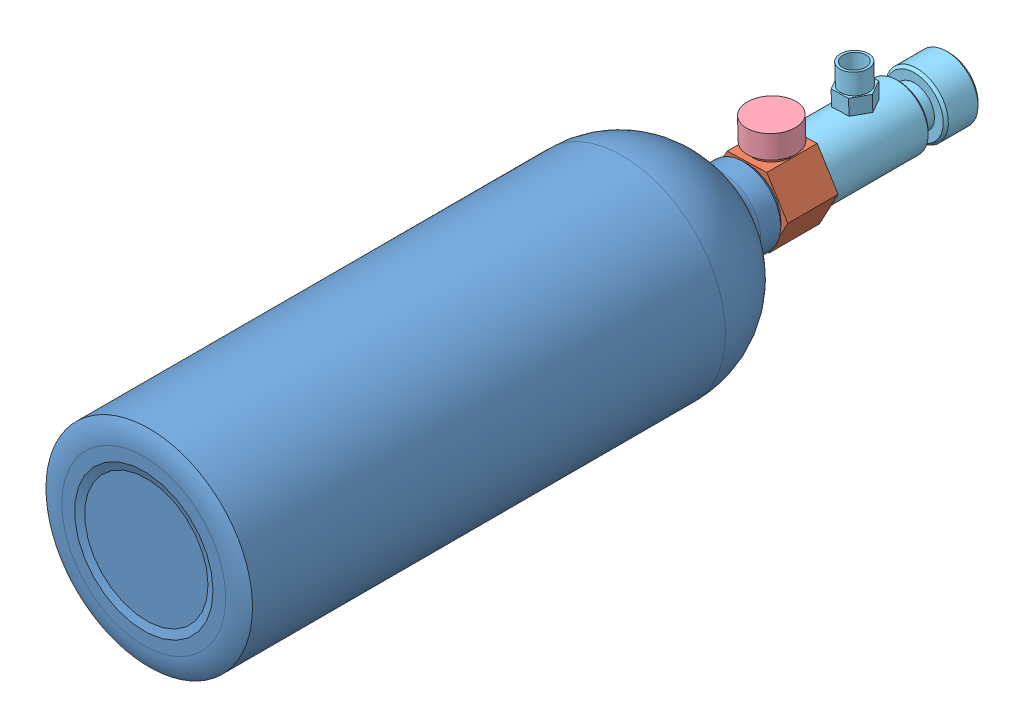
SolidWorks assembly Assem1, configuration Default. Lengths in mm.
Overall size (82 82 328.98).
5 component instances, 5 part files, 10 mates.
Components (placement in the parent):
- SE_01_2_1001-1: SE_01_2_1001 [Default] at origin size (82 82 240)
- SE_01_2_1002-1: SE_01_2_1002 [Default] at (0 0 -186.7314) x (-0.99947 -0.032561 0) z (0 0 -1) size (31.5 40.28 51)
- SE_01_2_1003-1: SE_01_2_1003 [Default] at (0 0 -220.7314) x (0.990256 -0.139258 0) z (0.139258 0.990256 0) size (18.5 2 18.5)
- SE_01_2_1004-1: SE_01_2_1004 [Default] at (-0.8023 24.6268 -196.7314) x (-0.179641 -0.005852 0.983715) z (0.032561 -0.99947 0) size (19 19 9)
- SE_01_2_1005-1: SE_01_2_1005 [Default] at (0 0 -251.5061) x (0.99947 0.032561 0) z (-0.032561 0.99947 0) size (70.53 79.28 39)
Mates (geometry in assembly coordinates):
- Concentric1: concentric anti-aligned: cylinder of SE_01_2_1001-1 through (0 0 52.2686) axis (0 0 1) radius 8; cylinder of SE_01_2_1002-1 through (0 0 -171.7314) axis (0 0 -1) radius 8
- Coincident1: coincident anti-aligned: plane of SE_01_2_1001-1 through (-8 0 -186.7314) normal (0 0 -1); plane of SE_01_2_1002-1 through (0 0 -186.7314) normal (0 0 1)
- Concentric2: concentric aligned: cylinder of SE_01_2_1002-1 through (-0.7372 22.6279 -196.7314) axis (0.032561 -0.99947 0) radius 7.5; cylinder of SE_01_2_1004-1 through (-0.7372 22.6279 -196.7314) axis (0.032561 -0.99947 0) radius 7.5
- Coincident2: coincident anti-aligned: plane of SE_01_2_1002-1 through (-0.7372 22.6279 -196.7314) normal (-0.032561 0.99947 0); plane of SE_01_2_1004-1 through (-0.7372 22.6279 -196.7314) normal (0.032561 -0.99947 0)
- Tangent8: tangent: plane of SE_01_2_1002-1 through (8.7454 0.2849 -221.7314) normal (0 0 1); torus of SE_01_2_1003-1
- Tangent9: tangent: cylinder of SE_01_2_1002-1 through (0 0 -227.3886) axis (0 0 -1) radius 7.25; torus of SE_01_2_1003-1
- Tangent10: tangent: plane of SE_01_2_1002-1 through (7.2462 0.2361 -219.7314) normal (0 0 -1); torus of SE_01_2_1003-1
- Concentric3: concentric aligned: cylinder of SE_01_2_1002-1 through (0 0 -216.7314) axis (0 0 1) radius 10; cylinder of SE_01_2_1005-1 through (0 0 -206.7314) axis (0 0 1) radius 9
- Coincident3: coincident anti-aligned: plane of SE_01_2_1002-1 through (0 0 -206.7314) normal (0 0 -1); plane of SE_01_2_1005-1 through (0 0 -206.7314) normal (0 0 1)
- Parallel1: parallel aligned: plane of SE_01_2_1004-1 through (-0.8023 24.6268 -196.7314) normal (-0.032561 0.99947 0); plane of SE_01_2_1005-1 through (-0.8629 26.4859 -229.7314) normal (-0.032561 0.99947 0)
